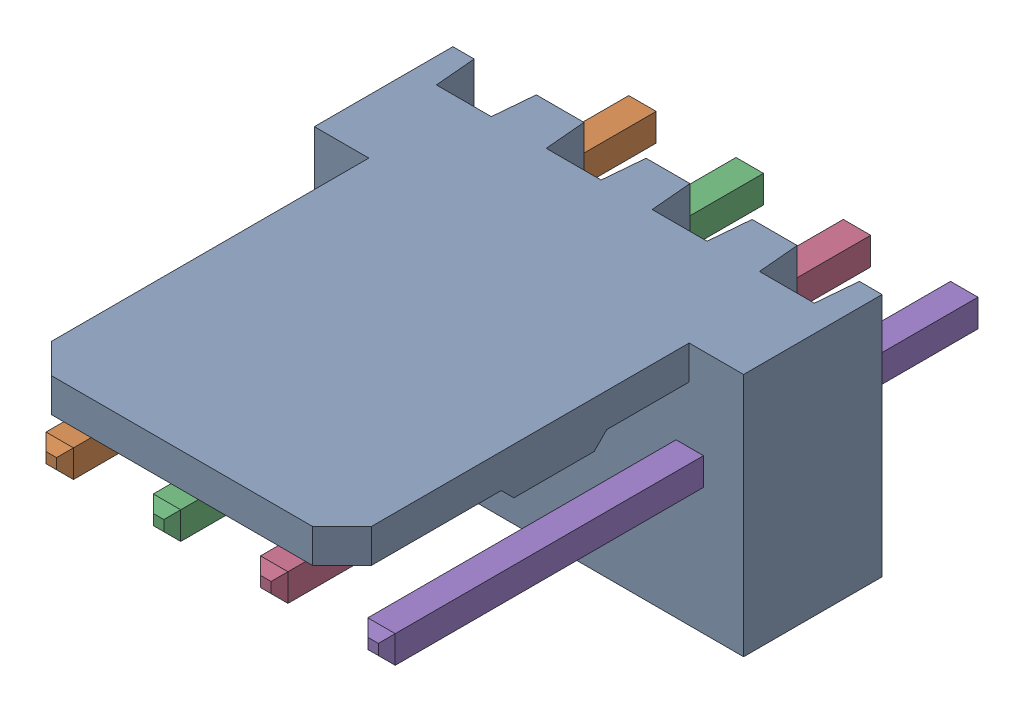
SolidWorks assembly Molex PCB 4 pin v3_2, configuration Default. Lengths in mm.
Overall size (10.16 5.79 14.92).
5 component instances, 2 part files, 0 mates.
Components (placement in the parent):
- BASE9710016 (2)-1: BASE9710016 (2) [Default] at (2.54 2.895 -8.22) size (10.16 5.79 11.5)
- PINO9710016 (2)-1: PINO9710016 (2) [Default] at (1.27 3.325 -0.72) size (0.65 0.65 14.2)
- PINO9710016 (2)-2: PINO9710016 (2) [Default] at (3.81 3.325 -0.72) size (0.65 0.65 14.2)
- PINO9710016 (2)-3: PINO9710016 (2) [Default] at (6.35 3.325 -0.72) size (0.65 0.65 14.2)
- PINO9710016 (2)-4: PINO9710016 (2) [Default] at (8.89 3.325 -0.72) size (0.65 0.65 14.2)
